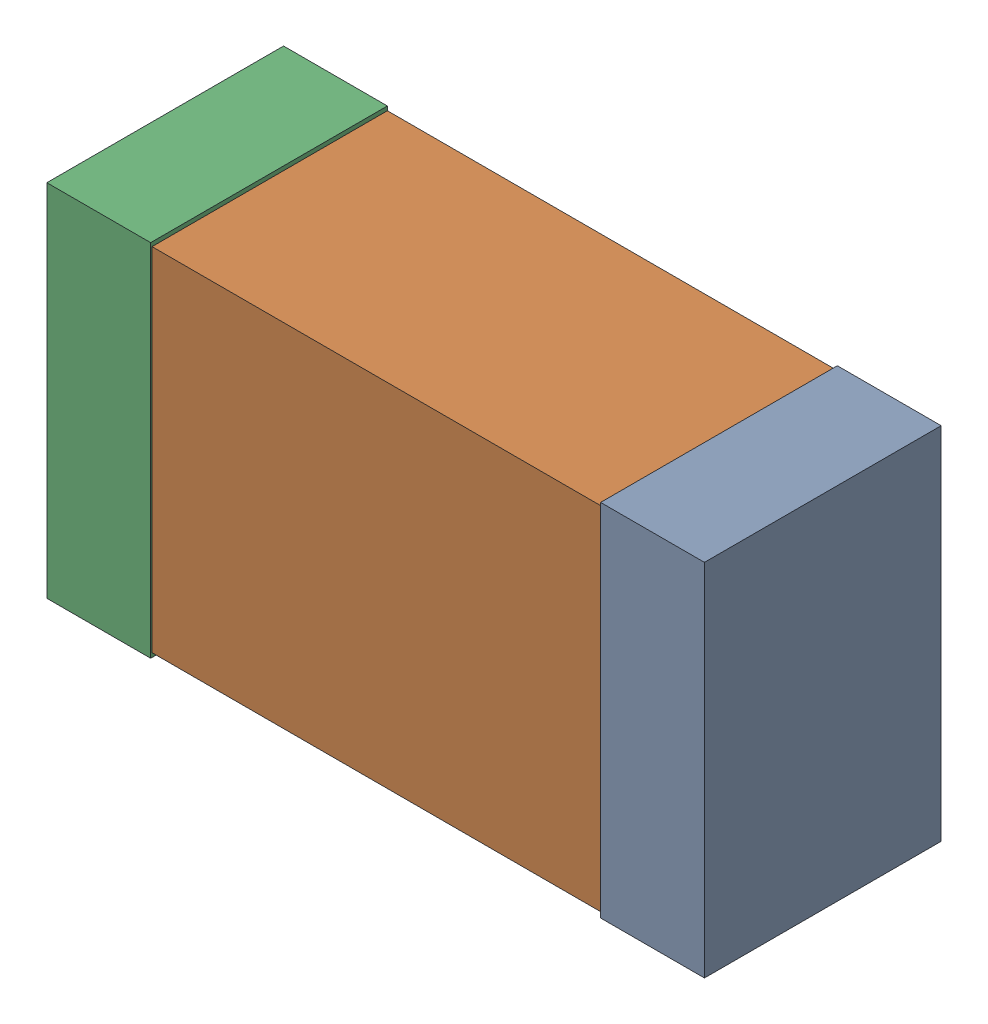
SolidWorks assembly Kanaloa_v2.0.0_Power_8, configuration Default. Lengths in mm.
Overall size (2.38 1.3 0.85).
6 component instances, 2 part files, 0 mates.
Components (placement in the parent):
- 352877648-1: 352877648 [Default] at (118.0256 104.0972 0) size (0.38 1.3 0.85)
  - Extruded_14-1: Extruded_14 [Default] at origin size (0.38 1.3 0.85)
- 352877904-1: 352877904 [Default] at (117.0256 104.0972 0) size (2.2 1.27 0.85)
  - Extruded_18-1: Extruded_18 [Default] at origin size (2.2 1.27 0.85)
- 352877648-2: 352877648 [Default] at (116.0256 104.0972 0) size (0.38 1.3 0.85)
  - Extruded_14-1: Extruded_14 [Default] at origin size (0.38 1.3 0.85)
